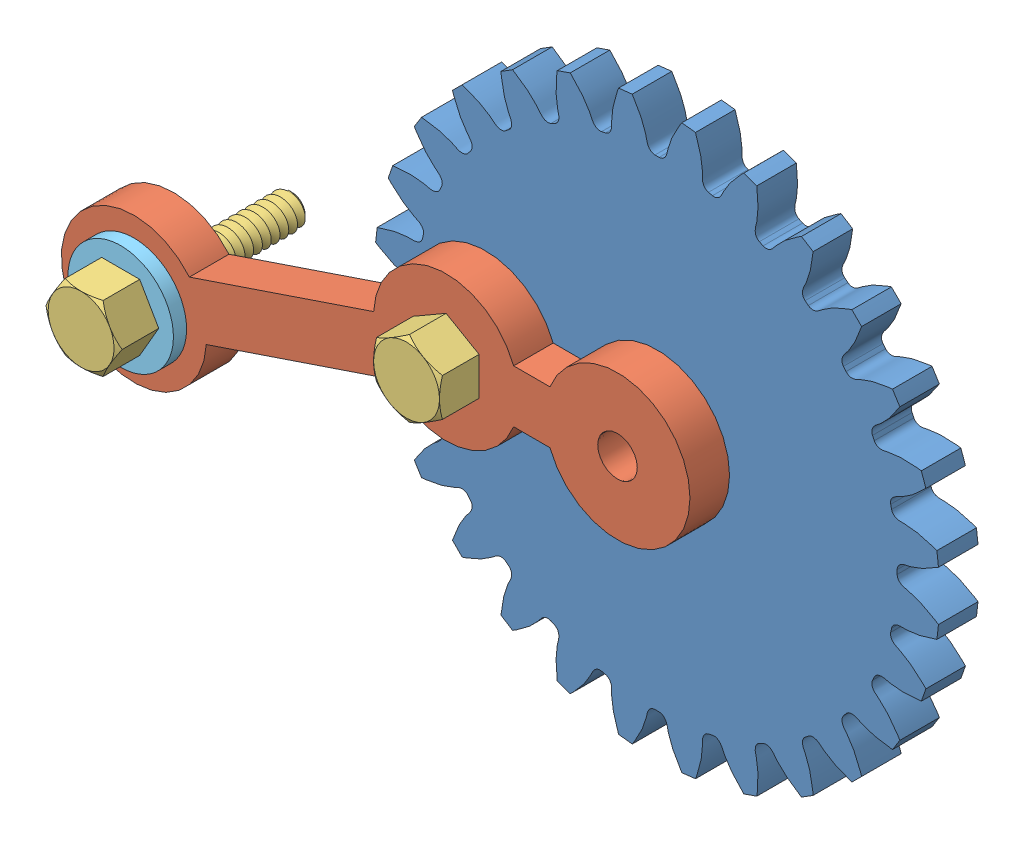
SolidWorks assembly Assem7_1, configuration Default. Lengths in mm.
Overall size (63.53 42.69 17.31).
7 component instances, 5 part files, 18 mates.
Components (placement in the parent):
- Part13-1: Part13 [Default] at origin size (42.69 42.69 3)
- Part9-1: Part9 [Default] at (0 0 1.5) x (-1 0 0) z (0 1 0) size (47.69 3 19)
- straf3_dolg13-2: straf3_dolg13 [Default] at (-13 0 4.5) x (0 0 1) z (-1 0 0) size (16.31 5.77 5)
- navrtka5-1: navrtka5 [Default] at (-13 0 -3) x (-1 0 0) z (0 0 1) size (5.57 5.77 3)
- straf3_dolg13-3: straf3_dolg13 [Default] at (-36.6854 -8 5.5) x (0 0 1) z (0 1 0) size (16.31 5.77 5)
- sajbna4-1: sajbna4 [Default] at (-36.6854 -8 5.5) x (1 0 0) z (0 1 0) size (8 1 8)
- sajbna4-2: sajbna4 [Default] at (-36.6854 -8 1.5) x (1 0 0) z (0 1 0) size (8 1 8)
Mates (geometry in assembly coordinates):
- Concentric1: concentric anti-aligned: cylinder of Part13-1 through (0 0 -1.5) axis (0 0 1) radius 1.5; cylinder of Part9-1 through (0 0 4.5) axis (0 0 -1) radius 1.5
- Coincident1: coincident anti-aligned: plane of Part13-1 through (0 0 1.5) normal (0 0 1); plane of Part9-1 through (0 0 1.5) normal (0 0 -1)
- Concentric2: concentric anti-aligned: cylinder of Part13-1 through (-13 0 -1.5) axis (0 0 1) radius 1.5; cylinder of Part9-1 through (-13 0 4.5) axis (0 0 -1) radius 1.5
- Concentric3: concentric anti-aligned: cylinder of Part9-1 through (-13 0 4.5) axis (0 0 -1) radius 1.5; cylinder of straf3_dolg13-2 through (-13 0 -8.5) axis (0 0 1) radius 1.5
- Coincident2: coincident anti-aligned: plane of Part9-1 through (0 0 4.5) normal (0 0 1); plane of straf3_dolg13-2 through (-13 0 4.5) normal (0 0 -1)
- Concentric4: concentric aligned: cylinder of Part13-1 through (-13 0 -1.5) axis (0 0 1) radius 1.5; circle of navrtka5-1
- Coincident3: coincident anti-aligned: plane of Part13-1 through (0 0 -1.5) normal (0 0 -1); plane of navrtka5-1 through (-13 0 -1.5) normal (0 0 1)
- Concentric5: concentric anti-aligned: cylinder of Part9-1 through (-36.6854 -8 4.5) axis (0 0 -1) radius 1.5; cylinder of straf3_dolg13-3 through (-36.6854 -8 -7.5) axis (0 0 1) radius 1.5
- Concentric6: concentric anti-aligned: cylinder of Part9-1 through (-36.6854 -8 4.5) axis (0 0 -1) radius 1.5; cylinder of sajbna4-1 through (-36.6854 -8 4.5) axis (0 0 1) radius 1.5
- Coincident4: coincident anti-aligned: plane of Part9-1 through (0 0 4.5) normal (0 0 1); plane of sajbna4-1 through (-36.6854 -8 4.5) normal (0 0 -1)
- Coincident5: coincident anti-aligned: plane of straf3_dolg13-3 through (-36.6854 -8 5.5) normal (0 0 -1); plane of sajbna4-1 through (-36.6854 -8 5.5) normal (0 0 1)
- Concentric8: concentric anti-aligned: cylinder of Part9-1 through (-36.6854 -8 4.5) axis (0 0 -1) radius 1.5; cylinder of sajbna4-2 through (-36.6854 -8 0.5) axis (0 0 1) radius 1.5
- Coincident6: coincident anti-aligned: plane of Part9-1 through (0 0 1.5) normal (0 0 -1); plane of sajbna4-2 through (-36.6854 -8 1.5) normal (0 0 1)
- Parallel1: parallel aligned: plane of straf3_dolg13-3 through (-36.6854 -8 5.5) normal (0 1 0); plane of assembly through (0 0 0) normal (0 1 0)
- Parallel5: parallel aligned: plane of sajbna4-1 through (-36.6854 -8 5.5) normal (0 1 0); plane of assembly through (0 0 0) normal (0 1 0)
- Parallel6: parallel aligned: plane of sajbna4-2 through (-36.6854 -8 1.5) normal (0 1 0); plane of assembly through (0 0 0) normal (0 1 0)
- Parallel7: parallel aligned: plane of straf3_dolg13-2; plane of assembly through (0 0 0) normal (0 1 0)
- Parallel8: parallel anti-aligned: plane of navrtka5-1; plane of assembly through (0 0 0) normal (0 1 0)
